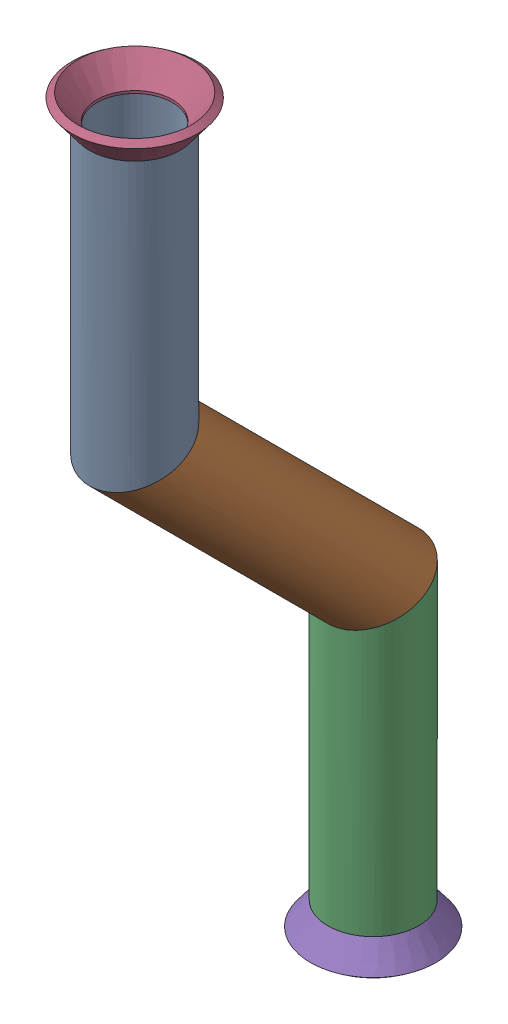
SolidWorks assembly Pipe 39, configuration Default. Lengths in mm.
Overall size (23.52 118.64 54).
3 component instances, 2 part files, 4 mates.
Components (placement in the parent):
- Part3-1: Part3 [Default<As Machined>] at origin size (12.7 110.86 46.14)
- Flared pipe end - .5 inch-1: Flared pipe end - .5 inch [Default<As Machined>] at (0 -187.7563 303.2502) x (0.999999 0 -0.001217) z (0 1 0) size (17.59 17.59 3.89)
- Flared pipe end - .5 inch-3: Flared pipe end - .5 inch [Default<As Machined>] at (0 -298.6197 269.8103) x (-0.899122 0 -0.437699) z (0 -1 0) size (17.59 17.59 3.89)
Mates (geometry in assembly coordinates):
- Coincident1054: coincident: plane of Part3-1 through (0 -187.7563 303.2502) normal (0 1 0); plane of Flared pipe end - .5 inch-1 through (-0.0064 -187.7563 297.967) normal (0 -1 0)
- Concentric661: concentric: circle of Part3-1; circle of Flared pipe end - .5 inch-1
- Coincident1070: coincident: plane of Part3-1 through (0 -298.6197 269.8103) normal (0 -1 0); plane of Flared pipe end - .5 inch-3 through (2.3125 -298.6197 265.06) normal (0 1 0)
- Coincident1071: coincident: circle of Part3-1; circle of Flared pipe end - .5 inch-3
